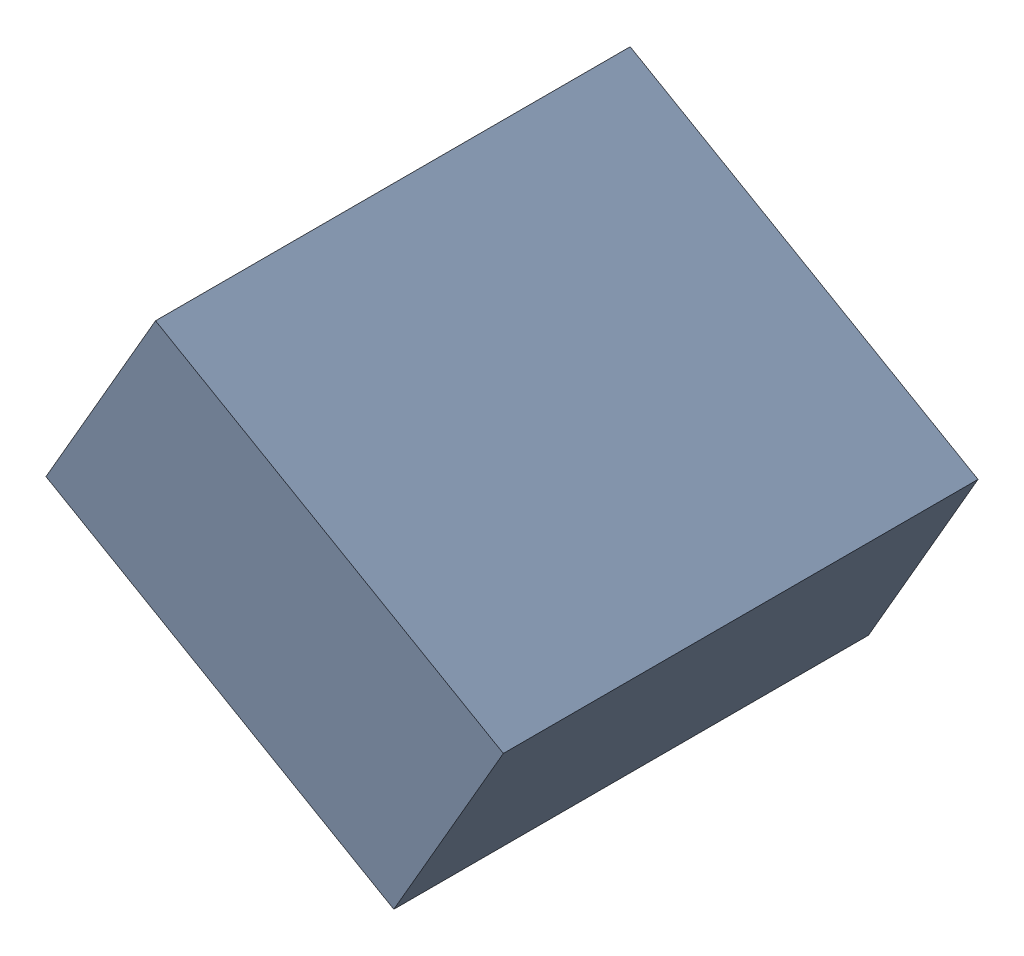
SolidWorks assembly C21_TDA6, configuration Standard. Lengths in mm.
Overall size (1.25 1.07 1.3).
2 component instances, 1 part files, 0 mates.
Components (placement in the parent):
- 885543056-1: 885543056 [Standard] at (-44.5724 22.7908 0) size (1.25 1.07 1.3)
  - Extruded_23-1: Extruded_23 [Standard] at origin size (1.25 1.07 1.3)
